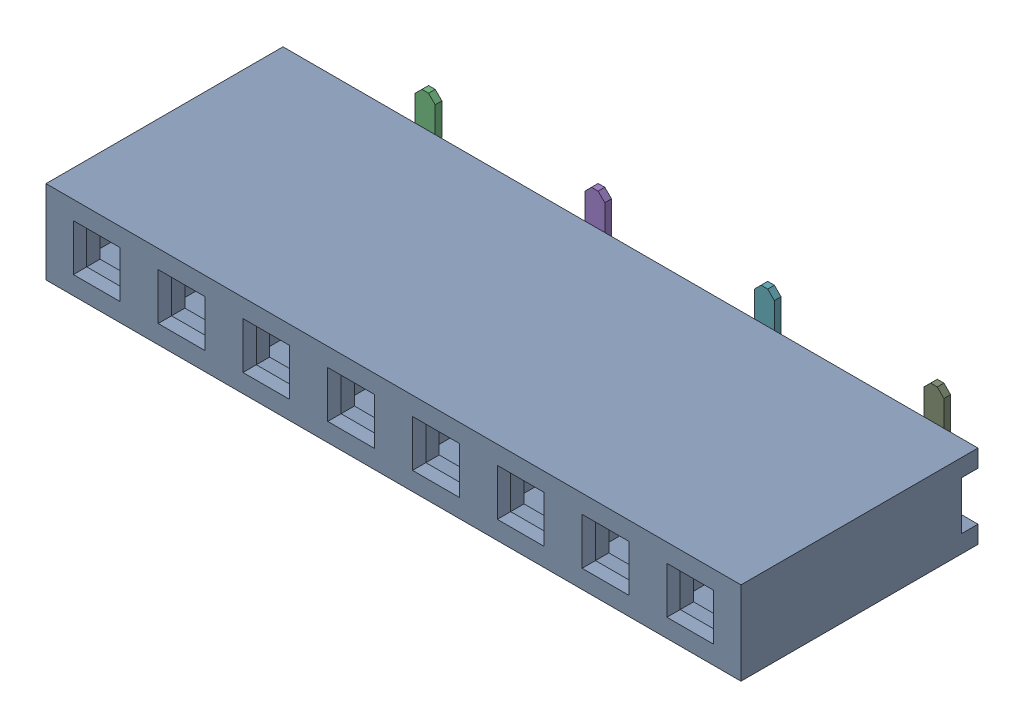
SolidWorks assembly J2, configuration Default. Lengths in mm.
Overall size (20.82 4.05 7.5).
10 component instances, 2 part files, 0 mates.
Components (placement in the parent):
- 61000813321-1: 61000813321 [Default] at (23.4999 3.5 3.95) x (1 0 0) z (0 0 1) size (20.82 4.05 7.5)
  - 6100081xx21-1: 6100081xx21 [Default] at origin size (20.82 2.5 7.1)
  - 6100xx1xx21_PIN-1: 6100xx1xx21_PIN [Default] at (-8.89 -0.725 -3.04) x (-1 0 0) z (0 0 -1) size (2 2.81 6.11)
  - 6100xx1xx21_PIN-2: 6100xx1xx21_PIN [Default] at (-6.35 0.725 -3.04) x (1 0 0) z (0 0 -1) size (2 2.81 6.11)
  - 6100xx1xx21_PIN-3: 6100xx1xx21_PIN [Default] at (-3.81 -0.725 -3.04) x (-1 0 0) z (0 0 -1) size (2 2.81 6.11)
  - 6100xx1xx21_PIN-4: 6100xx1xx21_PIN [Default] at (-1.27 0.725 -3.04) x (1 0 0) z (0 0 -1) size (2 2.81 6.11)
  - 6100xx1xx21_PIN-5: 6100xx1xx21_PIN [Default] at (1.27 -0.725 -3.04) x (-1 0 0) z (0 0 -1) size (2 2.81 6.11)
  - 6100xx1xx21_PIN-6: 6100xx1xx21_PIN [Default] at (3.81 0.725 -3.04) x (1 0 0) z (0 0 -1) size (2 2.81 6.11)
  - 6100xx1xx21_PIN-7: 6100xx1xx21_PIN [Default] at (6.35 -0.725 -3.04) x (-1 0 0) z (0 0 -1) size (2 2.81 6.11)
  - 6100xx1xx21_PIN-8: 6100xx1xx21_PIN [Default] at (8.89 0.725 -3.04) x (1 0 0) z (0 0 -1) size (2 2.81 6.11)
